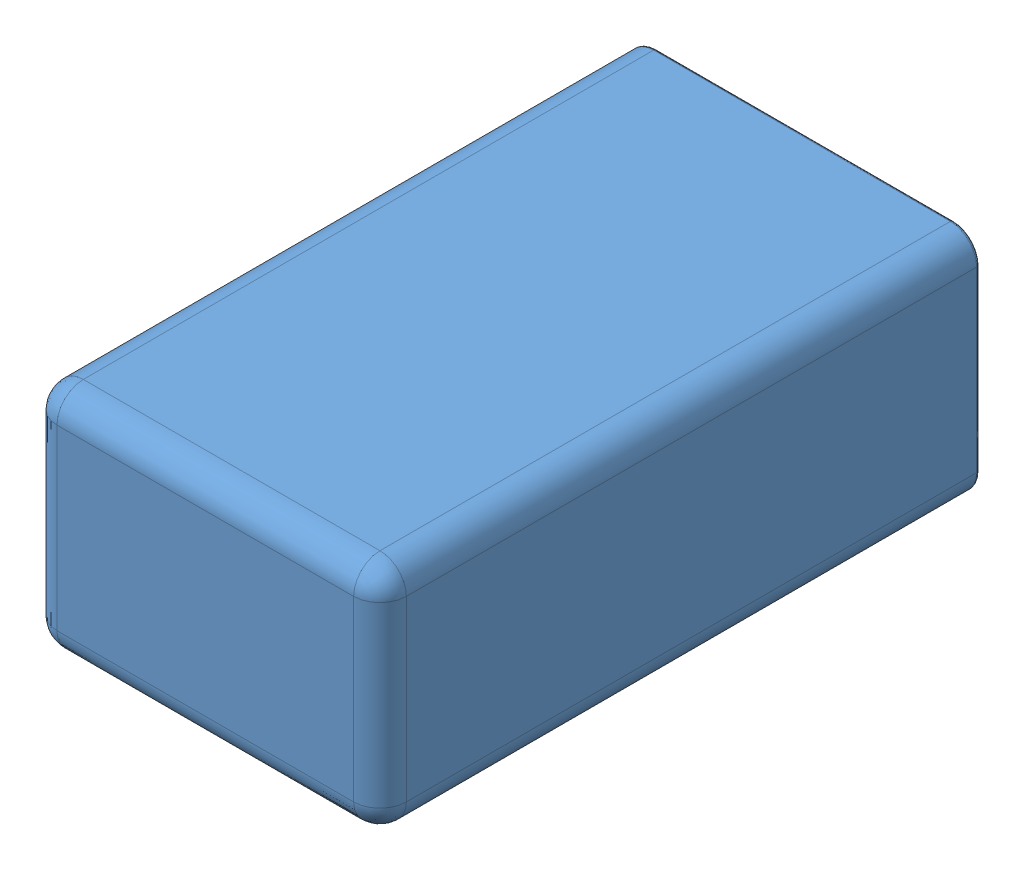
SolidWorks assembly 9V_Batterie, configuration ﾃﾞﾌｫﾙﾄ. Lengths in mm.
Overall size (26.5 17.5 49.03).
3 component instances, 3 part files, 8 mates.
Components (placement in the parent):
- Corps Batterie-1: Corps Batterie [ﾃﾞﾌｫﾙﾄ] at origin size (26.5 17.5 45.5)
- Connecteur femelle Batterie 9V-1: Connecteur femelle Batterie 9V [ﾃﾞﾌｫﾙﾄ] at (-6.5 0 0.5) x (1 0 0) z (0 1 0) size (8.07 5.34 8.38)
- Connecteur male Batterie 9V-1: Connecteur male Batterie 9V [ﾃﾞﾌｫﾙﾄ] at (6.5 0 0.5) x (0.847736 0.530419 0) z (-0.530419 0.847736 0) size (7 4.81 7)
Mates (geometry in assembly coordinates):
- 一致1: coincident aligned: plane of Corps Batterie-1 through (0 0 0) normal (1 0 0)
- 一致2: coincident aligned: plane of Corps Batterie-1 through (0 0 0) normal (0 0 1)
- 一致3: coincident aligned: plane of Corps Batterie-1 through (0 0 0) normal (0 1 0)
- 同心円1: concentric aligned: cylinder of Corps Batterie-1 through (6.5 0 1.5) axis (0 0 -1) radius 1.5; cylinder of Connecteur male Batterie 9V-1 through (6.5 0 1.5) axis (0 0 -1) radius 1.5
- 一致4: coincident anti-aligned: plane of Corps Batterie-1 through (11.6 -7 0.5) normal (0 0 -1); plane of Connecteur male Batterie 9V-1 through (1.6883 1.1079 0.5) normal (0 0 1)
- 一致5: coincident aligned: plane of Corps Batterie-1 through (11.6 -7 0.5) normal (0 0 -1); plane of Connecteur femelle Batterie 9V-1 through (-8.7785 -2.2785 0.5) normal (0 0 -1)
- 同心円2: concentric aligned: cylinder of Corps Batterie-1 through (-6.5 0 1.5) axis (0 0 -1) radius 1.5; cylinder of Connecteur femelle Batterie 9V-1 through (-6.5 0 1.5) axis (0 0 -1) radius 1.5
- 平行1: parallel anti-aligned: plane of Connecteur femelle Batterie 9V-1 through (-3.75 0 -1.05) normal (0 -1 0)
